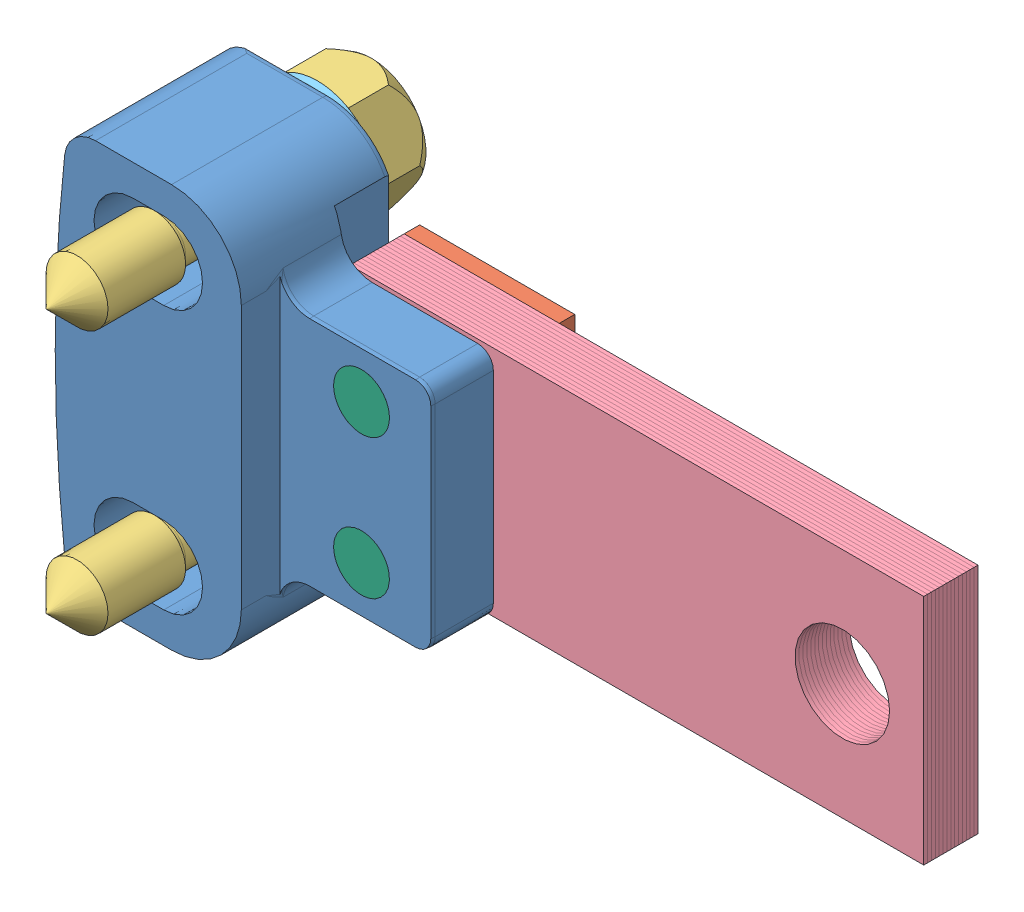
SolidWorks assembly 59676.0900ЧС, configuration Default. Lengths in mm.
Overall size (98.5 56.48 42).
25 component instances, 6 part files, 21 mates.
Components (placement in the parent):
- 59676.0905-1: 59676.0905 [Default] at origin size (43.5 52 20)
- 59676.0906-1: 59676.0906 [Default] at (49.6882 0 -4) size (74 30 0.5) (hidden)
- 59676.0903-1: 59676.0903 [Default] at (22.6882 0 -11) x (0 -1 0) z (0 0 -1) size (30 20 2)
- 59750-2201-1: 59750-2201 [Default] at (0 -17 -19.5) size (17.14 14 42)
- 59676.0906-2: 59676.0906 [Default] at (49.6882 0 -4.5) size (74 30 0.5)
- 59676.0906-3: 59676.0906 [Default] at (49.6882 0 -5) size (74 30 0.5)
- 59676.0906-4: 59676.0906 [Default] at (49.6882 0 -5.5) size (74 30 0.5)
- 59676.0906-5: 59676.0906 [Default] at (49.6882 0 -6) size (74 30 0.5)
- 59676.0906-6: 59676.0906 [Default] at (49.6882 0 -6.5) size (74 30 0.5)
- 59676.0906-7: 59676.0906 [Default] at (49.6882 0 -7) size (74 30 0.5)
- 59676.0906-8: 59676.0906 [Default] at (49.6882 0 -7.5) size (74 30 0.5)
- 59676.0906-9: 59676.0906 [Default] at (49.6882 0 -8) size (74 30 0.5)
- 59676.0906-10: 59676.0906 [Default] at (49.6882 0 -8.5) size (74 30 0.5)
- 59676.0906-11: 59676.0906 [Default] at (49.6882 0 -9) size (74 30 0.5)
- 59676.0906-12: 59676.0906 [Default] at (49.6882 0 -9.5) size (74 30 0.5)
- 59676.0906-13: 59676.0906 [Default] at (49.6882 0 -10) size (74 30 0.5)
- 59676.0906-14: 59676.0906 [Default] at (49.6882 0 -10.5) size (74 30 0.5)
- 59676.0906-15: 59676.0906 [Default] at (49.6882 0 -11) size (74 30 0.5)
- Шайба пружинна 8 DIN 2093-1: Шайба пружинна 8 DIN 2093 [Default] at (0 -17 -12) x (0.623175 0.782082 0) z (0 0 1) size (16 16 1)
- Шайба пружинна 8 DIN 2093-2: Шайба пружинна 8 DIN 2093 [Default] at (0 -17 -11) x (0.623175 0.782082 0) z (0 0 1) size (16 16 1)
- Нит Ф5X16 DIN 661-1: Нит Ф5X16 DIN 661 [Default] at (22.6882 -9 -4.25) size (7.2 7.2 17.5)
- 59750-2201-2: 59750-2201 [Default] at (0 17 -19.5) x (-1 0 0) z (0 0 1) size (17.14 14 42)
- Шайба пружинна 8 DIN 2093-3: Шайба пружинна 8 DIN 2093 [Default] at (0 17 -12) x (0.623175 -0.782082 0) z (0 0 -1) size (16 16 1)
- Нит Ф5X16 DIN 661-2: Нит Ф5X16 DIN 661 [Default] at (22.6882 9 -4.25) x (1 0 0) z (0 0 -1) size (7.2 7.2 17.5)
- Шайба пружинна 8 DIN 2093-4: Шайба пружинна 8 DIN 2093 [Default] at (0 17 -11) x (0.623175 -0.782082 0) z (0 0 -1) size (16 16 1)
Mates (geometry in assembly coordinates):
- Coincident7: coordinate: point of 59676.0905-1; point of assembly
- Concentric1: concentric aligned: cylinder of 59676.0905-1 through (22.6882 -9 4.5) axis (0 0 1) radius 2.6; cylinder of 59676.0906-1 through (22.6882 -9 -3.5) axis (0 0 1) radius 2.6
- Concentric2: concentric aligned: cylinder of 59676.0905-1 through (22.6882 9 4.5) axis (0 0 1) radius 2.6; cylinder of 59676.0906-1 through (22.6882 9 -3.5) axis (0 0 1) radius 2.6
- Coincident8: coincident anti-aligned: plane of 59676.0905-1 through (0 0 -3.5) normal (0 0 -1); plane of 59676.0906-1 through (49.6882 0 -3.5) normal (0 0 1)
- Coincident9: coincident anti-aligned: plane of 59676.0903-1 through (22.6882 0 -11) normal (0 0 1); plane of 59676.0906-15 through (49.6882 0 -11) normal (0 0 -1)
- Concentric3: concentric anti-aligned: cylinder of 59676.0905-1 through (22.6882 -9 4.5) axis (0 0 1) radius 2.6; cylinder of 59676.0903-1 through (22.6882 -9 -13) axis (0 0 -1) radius 2.6
- Concentric4: concentric anti-aligned: cylinder of 59676.0905-1 through (22.6882 9 4.5) axis (0 0 1) radius 2.6; cylinder of 59676.0903-1 through (22.6882 9 -13) axis (0 0 -1) radius 2.6
- Concentric6: concentric anti-aligned: cylinder of 59750-2201-1 through (0 -17 -30.6629) axis (0 0 -1) radius 3; cylinder of Шайба пружинна 8 DIN 2093-1 through (0 -17 -11.5) axis (0 0 1) radius 4.1
- Coincident10: coincident anti-aligned: plane of 59750-2201-1 through (0 -17 -12.5) normal (0 0 1); plane of Шайба пружинна 8 DIN 2093-1 through (0 -17 -12.5) normal (0 0 -1)
- Coincident11: coincident anti-aligned: plane of 59676.0905-1 through (0 0 -10.5) normal (0 0 -1); plane of Шайба пружинна 8 DIN 2093-2 through (-4.9854 -23.2567 -10.5) normal (0 0 1)
- Coincident12: coincident aligned: plane of 59676.0905-1 through (0 0 0) normal (1 0 0); plane of 59750-2201-1 through (0 -17 -19.5) normal (1 0 0)
- Coincident13: coincident aligned: plane of 59676.0905-1 through (0 -17 0) normal (0 1 0); plane of 59750-2201-1 through (0 -17 -19.5) normal (0 1 0)
- Coincident14: coincident aligned: plane of 59676.0905-1 through (0 0 4.5) normal (0 0 1); plane of Нит Ф5X16 DIN 661-1 through (20.0882 -9 4.5) normal (0 0 1)
- Concentric9: concentric anti-aligned: cylinder of 59676.0905-1 through (22.6882 -9 4.5) axis (0 0 1) radius 2.6; cylinder of Нит Ф5X16 DIN 661-1 through (22.6882 -9 -17.9095) axis (0 0 -1) radius 2.6
- Coincident15: coincident anti-aligned: plane of 59676.0903-1 through (22.4975 0 -8.5) normal (0 0 1); plane of 59676.0906-10 through (49.4975 0 -8.5) normal (0 0 -1)
- Coincident16: coincident aligned: plane of 59676.0905-1 through (0 0 4.5) normal (0 0 1); plane of ? through (19.9304 -9.4122 4.5) normal (0 0 1)
- Concentric10: concentric anti-aligned: cylinder of 59676.0905-1 through (22.4975 -9 4.5) axis (0 0 1) radius 2.6; cylinder of ? through (22.4975 -9 -16.6595) axis (0 0 -1) radius 2.6
- Coincident17: coincident aligned: plane of 59676.0905-1 through (0 0 4.5) normal (0 0 1); plane of ? through (19.8975 -9 4.5) normal (0 0 1)
- Concentric11: concentric anti-aligned: cylinder of 59676.0905-1 through (22.4975 -9 4.5) axis (0 0 1) radius 2.6; cylinder of ? through (22.4975 -9 -16.6595) axis (0 0 -1) radius 2.6
- Coincident18: coincident aligned: plane of 59676.0905-1 through (0 0 4.5) normal (0 0 1); plane of ? through (19.8975 -9 4.5) normal (0 0 1)
- Concentric12: concentric anti-aligned: cylinder of 59676.0905-1 through (22.4975 -9 4.5) axis (0 0 1) radius 2.6; cylinder of ? through (22.4975 -9 -17.9095) axis (0 0 -1) radius 2.6
